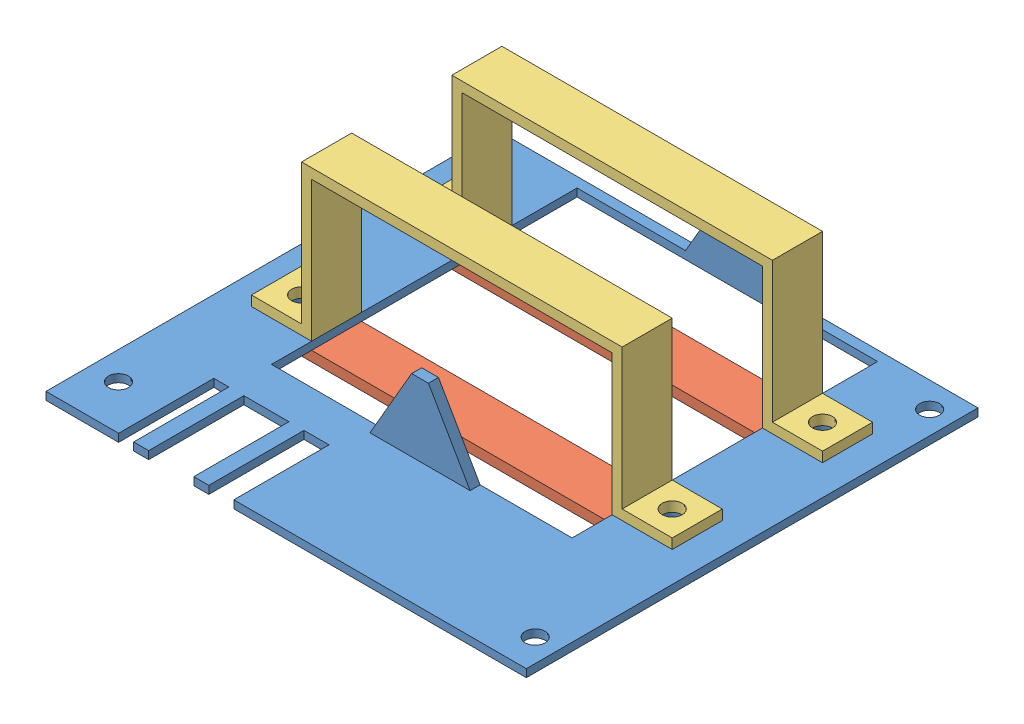
SolidWorks assembly BatteryHolderAssembly, configuration Default. Lengths in mm.
Overall size (95.89 33.57 90.17).
5 component instances, 3 part files, 13 mates.
Components (placement in the parent):
- BatteryFrontBoard-1: BatteryFrontBoard [Default] at (6.421 32.469 101.041) size (95.89 15.98 90.17)
- BatteryHolderRear-1: BatteryHolderRear [Default] at (44.3861 32.469 11.4906) x (1 0 0) z (0 -1 0) size (84 10 2)
- BatteryHolder-1: BatteryHolder [Default] at (27.9555 55.3923 37.322) size (84 30 10)
- BatteryHolderRear-2: BatteryHolderRear [Default] at (44.3861 30.469 43.1534) x (1 0 0) z (0 1 0) size (84 10 2)
- BatteryHolder-2: BatteryHolder [Default] at (27.9555 55.3923 7.322) size (84 30 10)
Mates (geometry in assembly coordinates):
- Coincident1: coincident anti-aligned: plane of BatteryFrontBoard-1 through (6.421 34.039 101.041) normal (0 1 0); plane of BatteryHolder-1 through (54.527 34.039 47.322) normal (0 -1 0)
- Concentric1: concentric aligned: circle of BatteryFrontBoard-1; circle of BatteryHolder-1
- Parallel1: parallel aligned: line of BatteryFrontBoard-1 through (70.567 34.039 -7.678) axis (0 0 1); line of BatteryHolder-2 through (64.527 36.039 7.322) axis (0 0 1)
- Parallel2: parallel aligned: line of BatteryFrontBoard-1 through (70.567 34.039 -7.678) axis (0 0 1); line of BatteryHolder-1 through (64.527 36.039 37.322) axis (0 0 1)
- Coincident7: coincident anti-aligned: plane of BatteryFrontBoard-1 through (6.421 32.469 101.041) normal (0 -1 0); plane of BatteryHolderRear-1 through (44.3861 32.469 11.4906) normal (0 1 0)
- Concentric3: concentric aligned: circle of BatteryFrontBoard-1; circle of BatteryHolderRear-1
- Parallel3: parallel aligned: plane of BatteryFrontBoard-1 through (70.567 24.039 82.492) normal (1 0 0); plane of BatteryHolderRear-1 through (64.527 30.469 7.322) normal (1 0 0)
- Coincident11: coincident anti-aligned: plane of BatteryFrontBoard-1 through (6.421 32.469 101.041) normal (0 -1 0); plane of BatteryHolderRear-2 through (44.3861 32.469 43.1534) normal (0 1 0)
- Coincident14: coincident aligned: circle of BatteryFrontBoard-1; circle of BatteryHolderRear-2
- Parallel4: parallel aligned: plane of BatteryFrontBoard-1 through (70.567 24.039 82.492) normal (1 0 0); plane of BatteryHolderRear-2 through (64.527 32.469 47.322) normal (1 0 0)
- Coincident16: coincident anti-aligned: plane of BatteryFrontBoard-1 through (6.421 34.039 101.041) normal (0 1 0); plane of BatteryHolder-2 through (54.527 34.039 17.322) normal (0 -1 0)
- Concentric4: concentric aligned: circle of BatteryFrontBoard-1; circle of BatteryHolder-2
- Parallel5: parallel aligned: plane of BatteryFrontBoard-1 through (70.567 24.039 82.492) normal (1 0 0); plane of BatteryHolder-2 through (64.527 26.039 7.322) normal (1 0 0)
